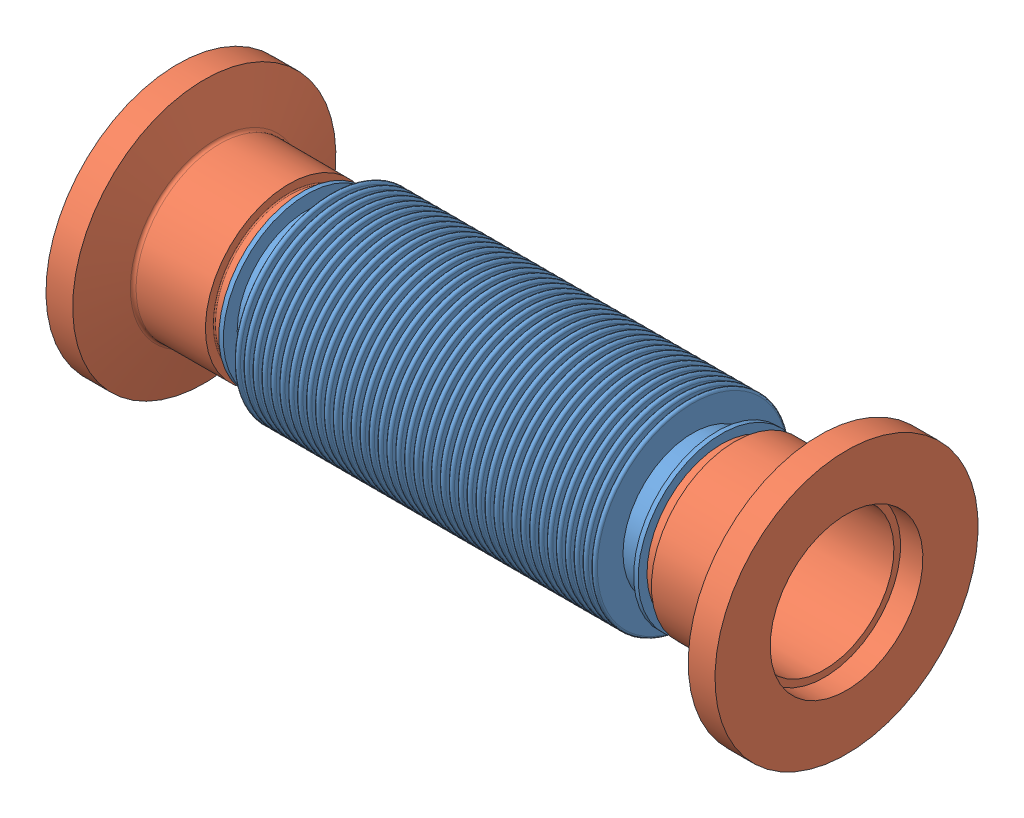
SolidWorks assembly 722000, configuration Default. Lengths in mm.
Overall size (76.2 42.17 42.17).
3 component instances, 2 part files, 4 mates.
Components (placement in the parent):
- SUB1-1: SUB1 [Default] at (20.1231 25.2831 35.1938) size (47.75 22.23 22.23)
- 713001-1: 713001 [Default] at (-17.9769 25.2831 35.1938) x (0 -0.327881 -0.944719) z (1 0 0) size (29.97 29.97 14.22)
- 713001-2: 713001 [Default] at (58.2231 25.2831 35.1938) x (0 0.631379 -0.775475) z (-1 0 0) size (29.97 29.97 14.22)
Mates (geometry in assembly coordinates):
- Concentric2: concentric aligned: cylinder of SUB1-1 through (43.9991 25.2831 35.1938) axis (1 0 0) radius 7.9375; cylinder of 713001-2 through (58.2231 25.2831 35.1938) axis (1 0 0) radius 9.525
- Coincident1: coincident anti-aligned: plane of SUB1-1 through (43.9991 25.2831 35.1938) normal (1 0 0); plane of 713001-2 through (43.9991 30.2947 29.0385) normal (-1 0 0)
- Concentric3: concentric anti-aligned: cylinder of SUB1-1 through (43.9991 25.2831 35.1938) axis (1 0 0) radius 7.9375; cylinder of 713001-1 through (-17.9769 25.2831 35.1938) axis (-1 0 0) radius 9.525
- Coincident2: coincident anti-aligned: plane of SUB1-1 through (-3.7529 25.2831 35.1938) normal (-1 0 0); plane of 713001-1 through (-3.7529 22.6806 27.6951) normal (1 0 0)
